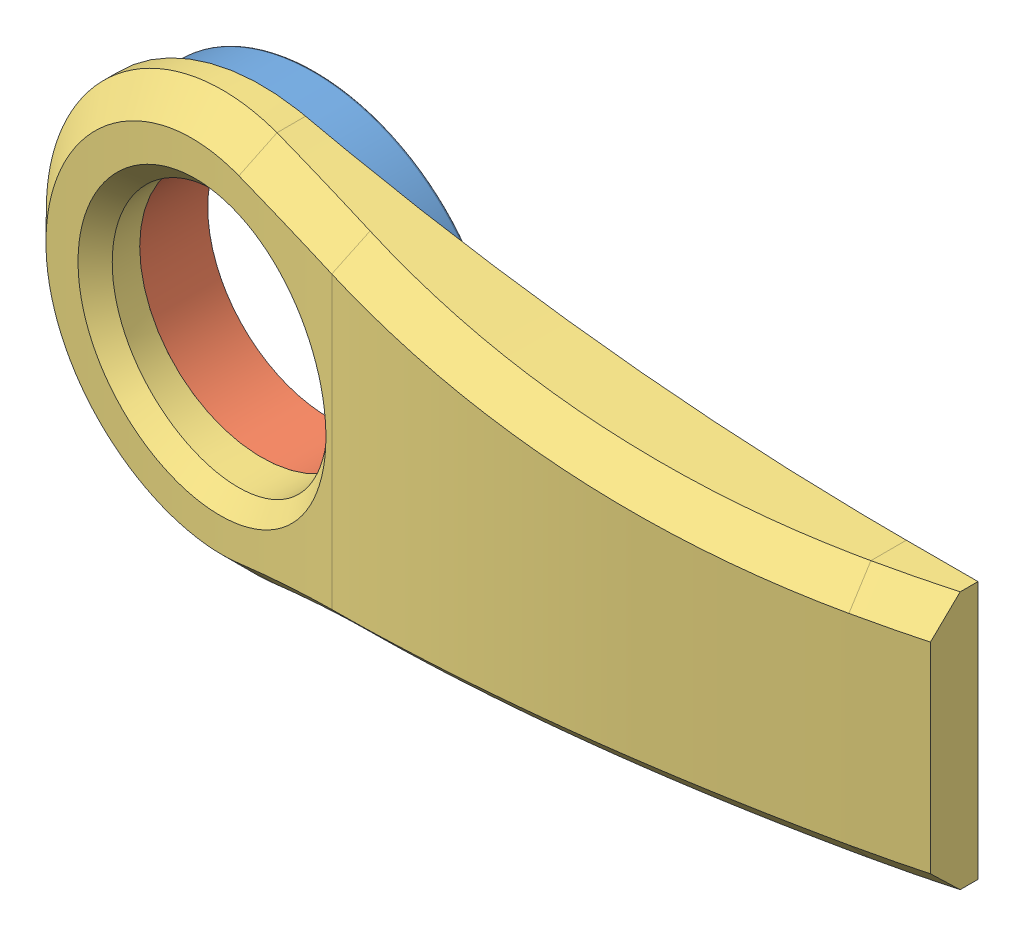
SolidWorks assembly Rahmen-Hinten, configuration Links. Lengths in mm.
Overall size (130.5 61 25.5).
4 component instances, 4 part files, 12 mates.
Components (placement in the parent):
- Kugellager - 61808 6808-1: Kugellager - 61808 6808 [Standard] at origin
- Rad-Hinten-Aufnahme-1: Rad-Hinten-Aufnahme [Standard] at (0 0 3.5)
- Rahmen-Hinten-1: Rahmen-Hinten [Standard] at (0 0 4) size (130.5 61 16.83)
- Lager-Abstandsscheibe-1: Lager-Abstandsscheibe [Innen] at (0 0 3.75)
Mates (geometry in assembly coordinates):
- Deckungsgleich23: coincident anti-aligned: plane of Rad-Hinten-Aufnahme-1 through (0 0 4) normal (0 0 1); plane of Rahmen-Hinten-1 through (0 0 4) normal (0 0 -1)
- Konzentrisch2: concentric anti-aligned: cylinder of Kugellager - 61808 6808-1 through (0 0 0) axis (0 0 1) radius 26; cylinder of Rahmen-Hinten-1 through (0 0 24) axis (0 0 -1) radius 30.5
- Deckungsgleich16: coincident aligned: plane of Rahmen-Hinten-1 through (0 0 4) normal (0 1 0); plane of assembly through (0 0 0) normal (0 1 0)
- Deckungsgleich17: coincident aligned: plane of Kugellager - 61808 6808-1 through (0 0 0) normal (0 0 1); plane of assembly through (0 0 0) normal (0 0 1)
- Deckungsgleich18: coincident aligned: plane of Kugellager - 61808 6808-1 through (0 0 0) normal (0 1 0); plane of assembly through (0 0 0) normal (0 1 0)
- Deckungsgleich19: coincident aligned: plane of Kugellager - 61808 6808-1 through (0 0 0) normal (1 0 0); plane of assembly through (0 0 0) normal (1 0 0)
- Deckungsgleich20: coincident aligned: plane of Kugellager - 61808 6808-1 through (0 0 0) normal (1 0 0); plane of Rad-Hinten-Aufnahme-1 through (0 0 3.5) normal (1 0 0)
- Deckungsgleich21: coincident aligned: plane of Kugellager - 61808 6808-1 through (0 0 0) normal (0 1 0); plane of Rad-Hinten-Aufnahme-1 through (0 0 3.5) normal (0 1 0)
- Deckungsgleich22: coincident aligned: plane of Kugellager - 61808 6808-1 through (0 0 3.5) normal (0 0 1); plane of Rad-Hinten-Aufnahme-1 through (0 0 3.5) normal (0 0 1)
- Deckungsgleich24: coincident aligned: plane of Lager-Abstandsscheibe-1 through (0 0 3.75) normal (1 0 0); plane of assembly through (0 0 0) normal (1 0 0)
- Deckungsgleich26: coincident aligned: plane of Lager-Abstandsscheibe-1 through (0 0 3.75) normal (0 1 0); plane of assembly through (0 0 0) normal (0 1 0)
- Deckungsgleich29: coincident anti-aligned: plane of Rahmen-Hinten-1 through (0 0 4) normal (0 0 -1); plane of Lager-Abstandsscheibe-1 through (0 0 4) normal (0 0 1)
